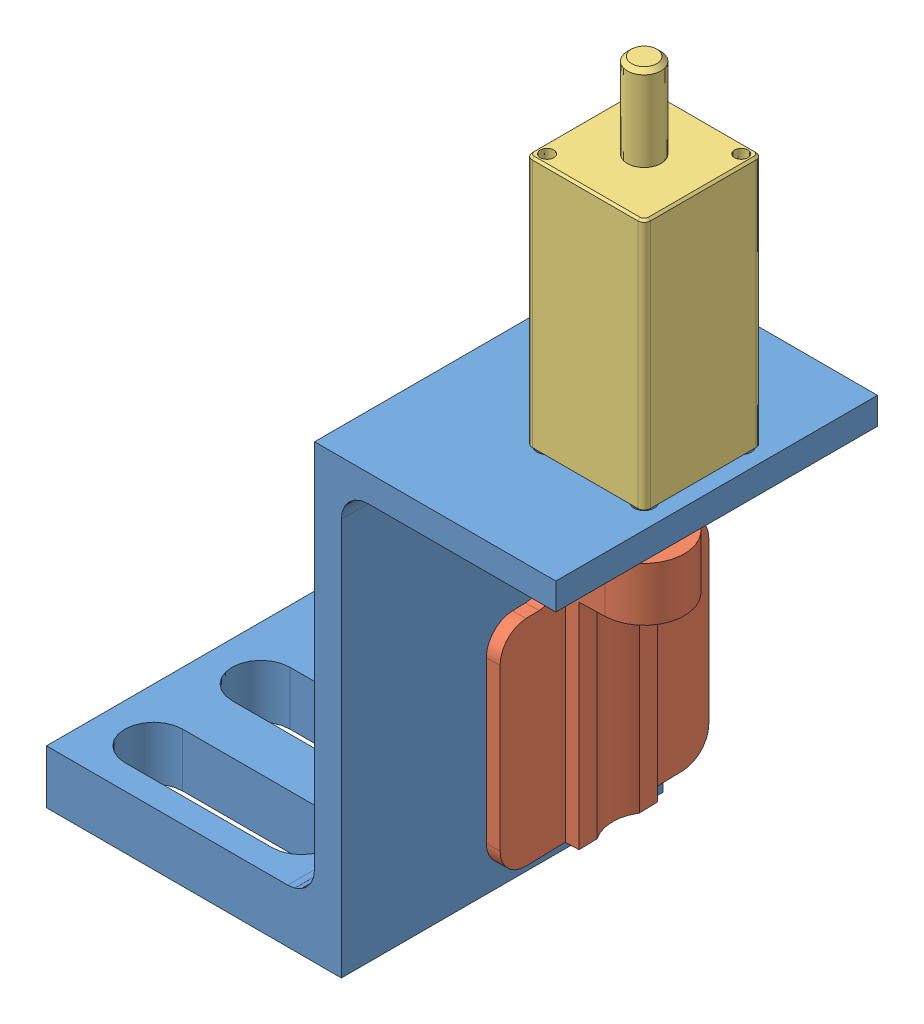
SolidWorks assembly Test Mirror X Assembly, configuration Default. Lengths in mm.
Overall size (60.32 93.42 38.1).
3 component instances, 3 part files, 8 mates.
Components (placement in the parent):
- Test X Mirror Mount-1: Test X Mirror Mount [Default] at (-16.8125 0 0) size (60.32 53.42 38.1)
- Square Mirror Mount-1: Square Mirror Mount [Default] at (0 25.7162 0) x (-0.026239 0 -0.999656) z (0.999656 0 -0.026239) size (25.4 31.75 10.94)
- SH2141-5511-1: SH2141-5511 [Default] at (0 53.4162 0) x (1 0 0) z (0 1 0) size (14 14 55)
Mates (geometry in assembly coordinates):
- Coincident1: coincident anti-aligned: plane of Test X Mirror Mount-1 through (8.5875 53.4162 19.05) normal (0 1 0); plane of SH2141-5511-1 through (0 53.4162 0) normal (0 -1 0)
- Distance1: distance = 1.5875 mm aligned: plane of Test X Mirror Mount-1 through (8.5875 50.2412 19.05) normal (1 0 0); plane of SH2141-5511-1 through (7 83.4162 -7) normal (1 0 0)
- Coincident3: coincident anti-aligned: plane of Test X Mirror Mount-1 through (-51.7375 0 19.05) normal (0 -1 0); plane of assembly through (0 0 0) normal (0 1 0)
- Coincident4: coincident aligned: plane of Test X Mirror Mount-1 through (-16.8125 0 0) normal (0 0 1); plane of assembly through (0 0 0) normal (0 0 1)
- Coincident5: coincident: axis of SH2141-5511-1 through (9.5 0 92.9162) axis (0 0 -1); plane of assembly
- Coincident6: coincident: axis of SH2141-5511-1 through (9.5 0 92.9162) axis (0 0 -1); plane of assembly
- Concentric1: concentric aligned: cylinder of Square Mirror Mount-1 through (0 13.0162 0) axis (0 1 0) radius 2.1; cylinder of SH2141-5511-1 through (0 17.7593 0) axis (0 1 0) radius 2
- Coincident7: coincident aligned: plane of Square Mirror Mount-1 through (4.6359 38.4162 -4.8858) normal (0 -1 0); plane of SH2141-5511-1 through (0 38.4162 0) normal (0 -1 0)
